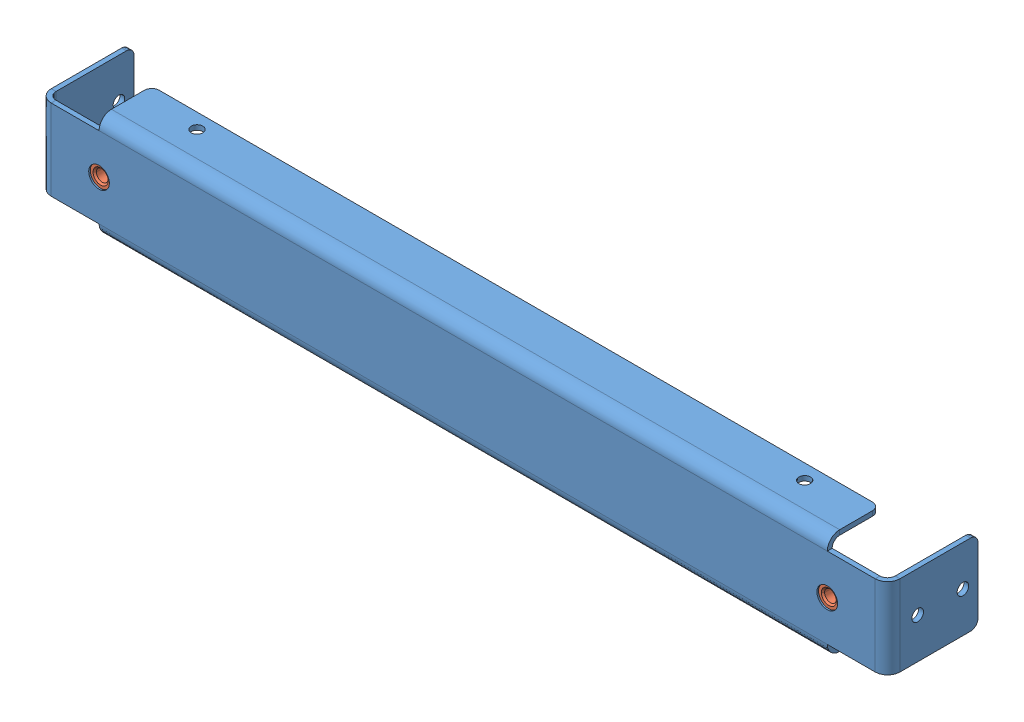
SolidWorks assembly GE-25013, configuration Default. Lengths in mm.
Overall size (357.63 44.45 38.1).
3 component instances, 2 part files, 4 mates.
Components (placement in the parent):
- GE-25013-01-1: GE-25013-01 [Default] at (-37.7266 242.1503 361.6688) size (357.63 44.45 38.1)
- pem_clinchnut_.25_20_.054-1: pem_clinchnut_.25_20_.054 [Default] at (-37.7266 264.3753 361.0084) x (0 0 -1) z (1 0 0) size (5.69 11.18 11.18)
- pem_clinchnut_.25_20_.054-2: pem_clinchnut_.25_20_.054 [Default] at (269.1054 264.3753 361.0084) x (0 0 -1) z (1 0 0) size (5.69 11.18 11.18)
Mates (geometry in assembly coordinates):
- Coincident1: coincident anti-aligned: plane of GE-24011-01-1 through (269.1054 242.1503 359.6368) normal (0 0 -1); plane of pem_clinchnut_.25_20_.054-1 through (-34.9326 264.3753 359.6368) normal (0 0 1)
- Concentric1: concentric anti-aligned: cylinder of GE-24011-01-1 through (-37.7266 264.3753 323.5688) axis (0 0 1) radius 4.3688; cylinder of pem_clinchnut_.25_20_.054-1 through (-37.7266 264.3753 357.6454) axis (0 0 -1) radius 5.588
- Concentric2: concentric: cylinder of GE-24011-01-1 through (269.1054 264.3753 323.5688) axis (0 0 1) radius 4.3688; cylinder of pem_clinchnut_.25_20_.054-2 through (269.1054 264.3753 357.6454) axis (0 0 -1) radius 5.588
- Coincident2: coincident anti-aligned: plane of GE-24011-01-1 through (269.1054 242.1503 359.6368) normal (0 0 -1); plane of pem_clinchnut_.25_20_.054-2 through (271.8994 264.3753 359.6368) normal (0 0 1)
